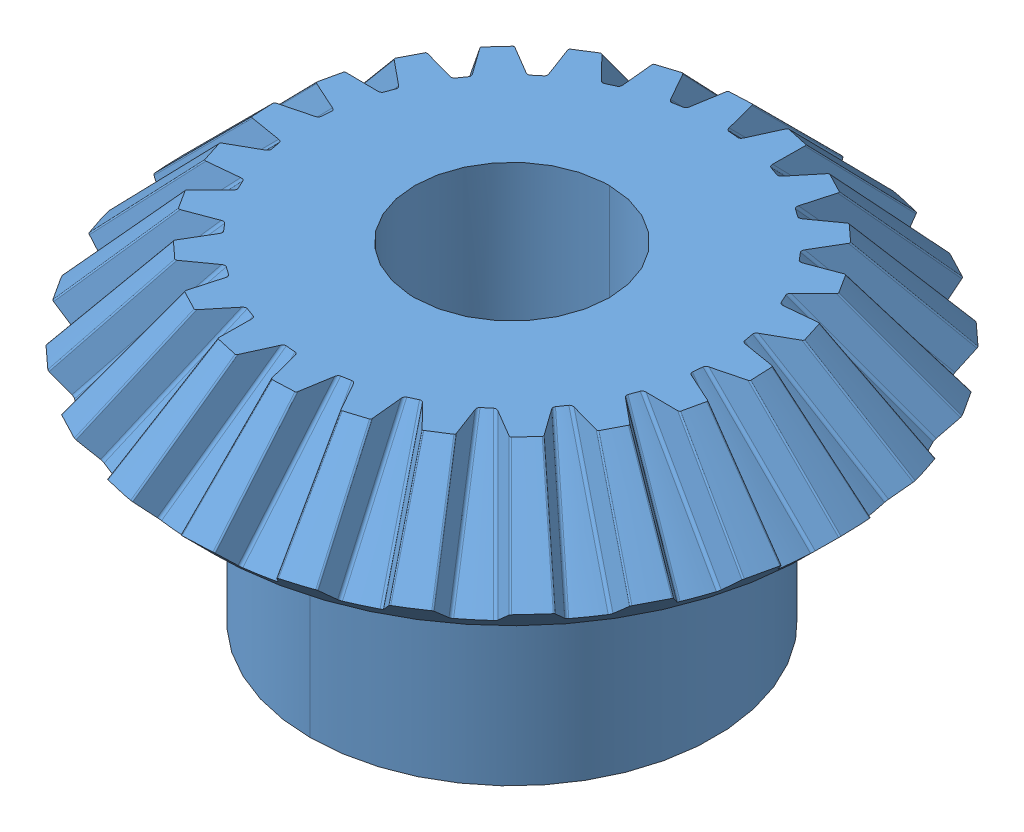
SolidWorks assembly 615406 assembly.STEP, configuration Default. Lengths in mm.
Overall size (20.35 10.41 20.35).
2 component instances, 2 part files, 0 mates.
Components (placement in the parent):
- 615406.STEP-1: 615406.STEP [Default] at (-74.1384 8.7571 33.0857) size (20.35 10.2 20.35)
- 632134_91375A436.STEP-1: 632134_91375A436.STEP [Default] at (-78.9723 6.9588 33.0857) x (0 -0.615223 0.788353) z (-1 0 0) size (4.83 4.83 3.18)
